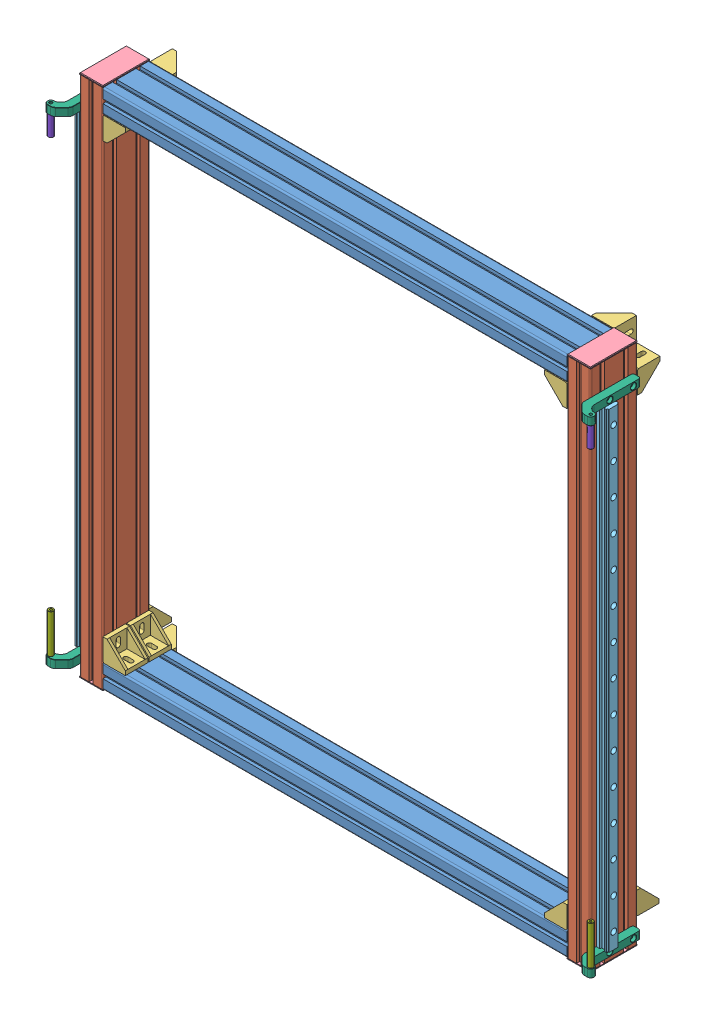
SolidWorks assembly Frame Top Stage, configuration Défaut. Lengths in mm.
Overall size (1047.13 1003 167.07).
34 component instances, 8 part files, 57 mates.
Components (placement in the parent):
- Frame X Top-1: Frame X Top [Défaut] at (-67 22.5 45) x (0 1 0) z (-1 0 0) size (45 90 888)
- Frame Y Top-1: Frame Y Top [Défaut] at (-3.2889 -2 75.8154) x (-1 0 0) z (0 -1 0) size (45 90 998)
- Frame X Top-2: Frame X Top [Défaut] at (-67 975.5 45) x (0 1 0) z (-1 0 0) size (45 90 888)
- Frame Y Top-2: Frame Y Top [Défaut] at (929.7111 -2 75.8154) x (-1 0 0) z (0 -1 0) size (45 90 998)
- nervure-1: nervure [Default] at (45 45 47) size (43 43 43)
- nervure-2: nervure [Default] at (45 953 47) x (0 -1 0) z (0 0 1) size (43 43 43)
- nervure-3: nervure [Default] at (933 45 47) x (0 1 0) z (0 0 1) size (43 43 43)
- nervure-4: nervure [Default] at (933 953 47) x (-1 0 0) z (0 0 1) size (43 43 43)
- nervure-5: nervure [Default] at (45 953 2) x (0 -1 0) z (0 0 1) size (43 43 43)
- nervure-6: nervure [Default] at (933 953 2) x (-1 0 0) z (0 0 1) size (43 43 43)
- nervure-7: nervure [Default] at (933 45 2) x (0 1 0) z (0 0 1) size (43 43 43)
- nervure-8: nervure [Default] at (45 45 2) size (43 43 43)
- Alu Profile End Cap 45x90-1: Alu Profile End Cap 45x90 [Défaut] at (22.5 0 45) x (0 0 1) z (0 -1 0) size (90 45 12.5)
- Alu Profile End Cap 45x90-5: Alu Profile End Cap 45x90 [Défaut] at (22.5 998 45) x (0 0 1) z (0 1 0) size (90 45 12.5)
- Alu Profile End Cap 45x90-6: Alu Profile End Cap 45x90 [Défaut] at (955.5 998 45) x (0 0 1) z (0 1 0) size (90 45 12.5)
- Alu Profile End Cap 45x90-4: Alu Profile End Cap 45x90 [Défaut] at (955.5 0 45) x (0 0 1) z (0 -1 0) size (90 45 12.5)
- nervure-9: nervure [Default] at (45 0 0) x (1 0 0) z (0 1 0) size (43 43 43)
- nervure-10: nervure [Default] at (43 45 0) x (0 1 0) z (-1 0 0) size (43 43 43)
- nervure-11: nervure [Default] at (933 45 0) x (-1 0 0) z (0 -1 0) size (43 43 43)
- nervure-12: nervure [Default] at (976 45 0) x (0 1 0) z (-1 0 0) size (43 43 43)
- nervure-13: nervure [Default] at (935 953 0) x (0 -1 0) z (1 0 0) size (43 43 43)
- nervure-14: nervure [Default] at (933 998 0) x (-1 0 0) z (0 -1 0) size (43 43 43)
- nervure-15: nervure [Default] at (2 953 0) x (0 -1 0) z (1 0 0) size (43 43 43)
- nervure-16: nervure [Default] at (45 953 0) x (1 0 0) z (0 1 0) size (43 43 43)
- HGR25-R1000-1: HGR25-R1000 [Default] at (989 485.5 67.5) x (0 0 -1) z (0 -1 0) size (23 22 900)
- HGR25-R1000-2: HGR25-R1000 [Default] at (-11 485.5 67.5) x (0 0 -1) z (0 1 0) size (23 22 900)
- Y Axis Stop-1: Y Axis Stop [Défaut] at (979.0859 950.5 84.2092) x (1 0 0) z (0 -1 0) size (34 114.75 15)
- Y Axis Stop-2: Y Axis Stop [Défaut] at (979.0859 35.5 84.2092) x (1 0 0) z (0 -1 0) size (34 114.75 15)
- Y Axis Stop-3: Y Axis Stop [Défaut] at (-1.0859 935.5 84.2092) x (-1 0 0) z (0 1 0) size (34 114.75 15)
- Y Axis Stop-4: Y Axis Stop [Défaut] at (-1.0859 20.5 84.2092) x (-1 0 0) z (0 1 0) size (34 114.75 15)
- EndStop Spacer 75mm-1: EndStop Spacer 75mm [Défaut] at (1005.5 35.5 117) x (0.737077 0 0.675809) z (0 1 0) size (10 10 85)
- EndStop Spacer 40mm-1: EndStop Spacer 40mm [Défaut] at (-27.5 935.5 117) x (-0.718383 0 -0.695648) z (0 -1 0) size (10 10 50)
- EndStop Spacer 75mm-2: EndStop Spacer 75mm [Défaut] at (-27.5 35.5 117) x (1 0 0) z (0 1 0) size (10 10 85)
- EndStop Spacer 40mm-2: EndStop Spacer 40mm [Défaut] at (1005.5 935.5 117) x (1 0 0) z (0 -1 0) size (10 10 50)
Mates (geometry in assembly coordinates):
- Coïncidente1: coincident anti-aligned: plane of Frame X Top-1 through (45 0 63.5) normal (0 -1 0); plane of assembly through (0 0 0) normal (0 1 0)
- Coïncidente2: coincident anti-aligned: plane of Frame X Top-1 through (45 3 0) normal (0 0 -1); plane of assembly through (0 0 0) normal (0 0 1)
- Distance1: distance = 45 mm: plane of assembly through (0 0 0) normal (1 0 0); plane of assembly; plane of Frame X Top-1 through (45 3 87) normal (-1 0 0)
- Coïncidente3: coincident aligned: plane of Frame X Top-1 through (45 0 63.5) normal (0 -1 0); plane of Frame Y Top-1 through (42 0 87) normal (0 -1 0)
- Coïncidente4: coincident aligned: plane of Frame X Top-1 through (45 42 90) normal (0 0 1); plane of Frame Y Top-1 through (26.5 0 90) normal (0 0 1)
- Coïncidente5: coincident anti-aligned: plane of Frame X Top-1 through (45 3 87) normal (-1 0 0); plane of Frame Y Top-1 through (45 0 63.5) normal (1 0 0)
- Coïncidente6: coincident aligned: plane of Frame X Top-1 through (45 18.5 90) normal (0 0 1); plane of Frame X Top-2 through (45 971.5 90) normal (0 0 1)
- Coïncidente7: coincident aligned: plane of Frame X Top-1 through (933 3 87) normal (1 0 0); plane of Frame X Top-2 through (933 956 87) normal (1 0 0)
- Coïncidente8: coincident aligned: plane of Frame X Top-1 through (45 18.5 90) normal (0 0 1); plane of Frame Y Top-2 through (936 0 90) normal (0 0 1)
- Coïncidente9: coincident aligned: plane of Frame X Top-1 through (45 0 63.5) normal (0 -1 0); plane of Frame Y Top-2 through (975 0 87) normal (0 -1 0)
- Coïncidente10: coincident anti-aligned: plane of Frame X Top-1 through (933 3 87) normal (1 0 0); plane of Frame Y Top-2 through (933 0 26.5) normal (-1 0 0)
- Coïncidente11: coincident aligned: plane of Frame X Top-2 through (45 998 26.5) normal (0 1 0); plane of Frame Y Top-2 through (975 998 87) normal (0 1 0)
- Coïncidente12: coincident aligned: plane of Frame X Top-1 through (45 42 90) normal (0 0 1); plane of nervure-1 through (45 45 90) normal (0 0 1)
- Coïncidente13: coincident anti-aligned: plane of Frame Y Top-1 through (45 0 87) normal (1 0 0); plane of nervure-1 through (45 88 90) normal (-1 0 0)
- Coïncidente14: coincident anti-aligned: plane of Frame X Top-1 through (45 45 71.5) normal (0 1 0); plane of nervure-1 through (45 45 90) normal (0 -1 0)
- Coïncidente15: coincident aligned: plane of Frame X Top-1 through (45 42 90) normal (0 0 1); plane of nervure-3 through (933 45 90) normal (0 0 1)
- Coïncidente16: coincident aligned: plane of Frame X Top-1 through (45 42 90) normal (0 0 1); plane of nervure-2 through (45 953 90) normal (0 0 1)
- Coïncidente17: coincident aligned: plane of Frame X Top-1 through (45 42 90) normal (0 0 1); plane of nervure-4 through (933 953 90) normal (0 0 1)
- Coïncidente18: coincident anti-aligned: plane of Frame Y Top-2 through (933 0 26.5) normal (-1 0 0); plane of nervure-3 through (933 45 90) normal (1 0 0)
- Coïncidente19: coincident anti-aligned: plane of Frame Y Top-2 through (933 0 26.5) normal (-1 0 0); plane of nervure-4 through (933 910 90) normal (1 0 0)
- Coïncidente20: coincident anti-aligned: plane of Frame X Top-2 through (45 953 63.5) normal (0 -1 0); plane of nervure-2 through (88 953 90) normal (0 1 0)
- Coïncidente21: coincident anti-aligned: plane of Frame X Top-2 through (45 953 63.5) normal (0 -1 0); plane of nervure-4 through (933 953 90) normal (0 1 0)
- Coïncidente22: coincident anti-aligned: plane of Frame X Top-1 through (45 45 26.5) normal (0 1 0); plane of nervure-3 through (890 45 90) normal (0 -1 0)
- Coïncidente23: coincident anti-aligned: plane of Frame Y Top-1 through (45 0 63.5) normal (1 0 0); plane of nervure-2 through (45 953 90) normal (-1 0 0)
- Coïncidente24: coincident anti-aligned: plane of Frame Y Top-1 through (42 0 87) normal (0 -1 0); plane of Alu Profile End Cap 45x90-1 through (22.5 0 45) normal (0 1 0)
- Coaxiale1: concentric anti-aligned: cylinder of Frame Y Top-1 through (22.5 0 67.5) axis (0 1 0) radius 4; cylinder of Alu Profile End Cap 45x90-1 through (22.5 10 67.5) axis (0 -1 0) radius 4
- Coaxiale2: concentric anti-aligned: cylinder of Frame Y Top-1 through (22.5 0 22.5) axis (0 1 0) radius 4; cylinder of Alu Profile End Cap 45x90-1 through (22.5 10 22.5) axis (0 -1 0) radius 4
- Coïncidente25: coincident anti-aligned: plane of Frame Y Top-1 through (42 998 87) normal (0 1 0); plane of Alu Profile End Cap 45x90-5 through (22.5 998 45) normal (0 -1 0)
- Coaxiale3: concentric aligned: cylinder of Frame Y Top-1 through (22.5 0 67.5) axis (0 1 0) radius 4; cylinder of Alu Profile End Cap 45x90-5 through (22.5 988 67.5) axis (0 1 0) radius 4
- Coaxiale4: concentric aligned: cylinder of Frame Y Top-1 through (22.5 0 22.5) axis (0 1 0) radius 4; cylinder of Alu Profile End Cap 45x90-5 through (22.5 988 22.5) axis (0 1 0) radius 4
- Coïncidente26: coincident anti-aligned: plane of Frame X Top-1 through (45 26.5 0) normal (0 0 -1); plane of nervure-9 through (45 43 0) normal (0 0 1)
- Coïncidente27: coincident anti-aligned: plane of Frame X Top-1 through (45 26.5 0) normal (0 0 -1); plane of nervure-10 through (0 45 0) normal (0 0 1)
- Coïncidente28: coincident aligned: plane of Frame X Top-1 through (45 0 18.5) normal (0 -1 0); plane of nervure-9 through (45 0 0) normal (0 -1 0)
- Coïncidente29: coincident anti-aligned: plane of Frame Y Top-1 through (45 0 63.5) normal (1 0 0); plane of nervure-9 through (45 43 -43) normal (-1 0 0)
- Coïncidente30: coincident anti-aligned: plane of Frame X Top-1 through (45 45 26.5) normal (0 1 0); plane of nervure-10 through (0 45 -43) normal (0 -1 0)
- Coïncidente31: coincident aligned: plane of Frame Y Top-1 through (0 0 26.5) normal (-1 0 0); plane of nervure-10 through (0 45 0) normal (-1 0 0)
- Coïncidente32: coincident anti-aligned: plane of Frame X Top-1 through (45 3 0) normal (0 0 -1); plane of nervure-12 through (933 45 0) normal (0 0 1)
- Coïncidente33: coincident anti-aligned: plane of Frame X Top-1 through (45 3 0) normal (0 0 -1); plane of nervure-11 through (933 2 0) normal (0 0 1)
- Coïncidente34: coincident aligned: plane of Frame Y Top-2 through (933 0 26.5) normal (-1 0 0); plane of nervure-12 through (933 45 0) normal (-1 0 0)
- Coïncidente35: coincident anti-aligned: plane of Frame X Top-1 through (45 45 26.5) normal (0 1 0); plane of nervure-12 through (933 45 -43) normal (0 -1 0)
- Coïncidente36: coincident aligned: plane of Frame X Top-1 through (45 45 26.5) normal (0 1 0); plane of nervure-11 through (933 45 0) normal (0 1 0)
- Coïncidente37: coincident anti-aligned: plane of Frame Y Top-2 through (933 0 26.5) normal (-1 0 0); plane of nervure-11 through (933 2 -43) normal (1 0 0)
- Coïncidente39: coincident anti-aligned: plane of Frame Y Top-2 through (978 0 63.5) normal (1 0 0); plane of HGR25-R1000-1 through (978 -14.5 78) normal (-1 0 0)
- Largeur2: width anti-aligned: plane of HGR25-R1000-1 through (979 -14.5 56) normal (0 0 -1); plane of Frame Y Top-2 through (984 -14.5 79) normal (0 0 1); plane of HGR25-R1000-1 through (972 0 63.5) normal (0 0 1); plane of Frame Y Top-2 through (978 0 71.5) normal (0 0 -1)
- Coïncidente41: coincident anti-aligned: plane of Frame Y Top-2 through (978 0 63.5) normal (1 0 0); plane of Y Axis Stop-1 through (978 935.5 12.75) normal (-1 0 0)
- Largeur6: width: plane of Frame Y Top-2 through (972 0 63.5) normal (0 0 1); plane of Y Axis Stop-1 through (978 0 71.5) normal (0 0 -1); cylinder of Frame Y Top-2 through (993 943 67.5) axis (1 0 0) radius 3.3
- Largeur7: width: plane of Frame Y Top-2 through (978 0 26.5) normal (0 0 -1); plane of Y Axis Stop-1 through (972 0 18.5) normal (0 0 1); cylinder of Frame Y Top-2 through (993 943 22.5) axis (1 0 0) radius 3.3
- Coïncidente51: coincident anti-aligned: plane of HGR25-R1000-1 through (978 935.5 188.6837) normal (0 1 0); plane of Y Axis Stop-1 through (1005.5 935.5 117) normal (0 -1 0)
- Distance8: distance = 20.5 mm anti-aligned: plane of Y Axis Stop-2 through (1005.5 20.5 117) normal (0 -1 0); plane of Alu Profile End Cap 45x90-4 through (955.5 0 45) normal (0 1 0)
- Coaxiale64: concentric anti-aligned: cylinder of Y Axis Stop-1 through (1005.5 935.5 117) axis (0 -1 0) radius 2.5; cylinder of EndStop Spacer 40mm-2 through (1005.5 895.5 117) axis (0 1 0) radius 5
- Coïncidente107: coincident anti-aligned: plane of Y Axis Stop-1 through (1005.5 935.5 117) normal (0 -1 0); plane of EndStop Spacer 40mm-2 through (1005.5 935.5 117) normal (0 1 0)
- Coaxiale65: concentric aligned: cylinder of Y Axis Stop-3 through (-27.5 950.5 117) axis (0 1 0) radius 2.5; cylinder of EndStop Spacer 40mm-1 through (-27.5 895.5 117) axis (0 1 0) radius 5
- Coïncidente108: coincident anti-aligned: plane of Y Axis Stop-3 through (-27.5 935.5 117) normal (0 -1 0); plane of EndStop Spacer 40mm-1 through (-27.5 935.5 117) normal (0 1 0)
- Coaxiale66: concentric aligned: cylinder of Y Axis Stop-2 through (1005.5 20.5 117) axis (0 -1 0) radius 2.5; cylinder of EndStop Spacer 75mm-1 through (1005.5 110.5 117) axis (0 -1 0) radius 5
- Coïncidente109: coincident anti-aligned: plane of Y Axis Stop-2 through (1005.5 35.5 117) normal (0 1 0); plane of EndStop Spacer 75mm-1 through (1005.5 35.5 117) normal (0 -1 0)
- Coaxiale67: concentric anti-aligned: cylinder of Y Axis Stop-4 through (-27.5 35.5 117) axis (0 1 0) radius 2.5; cylinder of EndStop Spacer 75mm-2 through (-27.5 110.5 117) axis (0 -1 0) radius 5
- Coïncidente110: coincident anti-aligned: plane of Y Axis Stop-4 through (-27.5 35.5 117) normal (0 1 0); plane of EndStop Spacer 75mm-2 through (-27.5 35.5 117) normal (0 -1 0)
